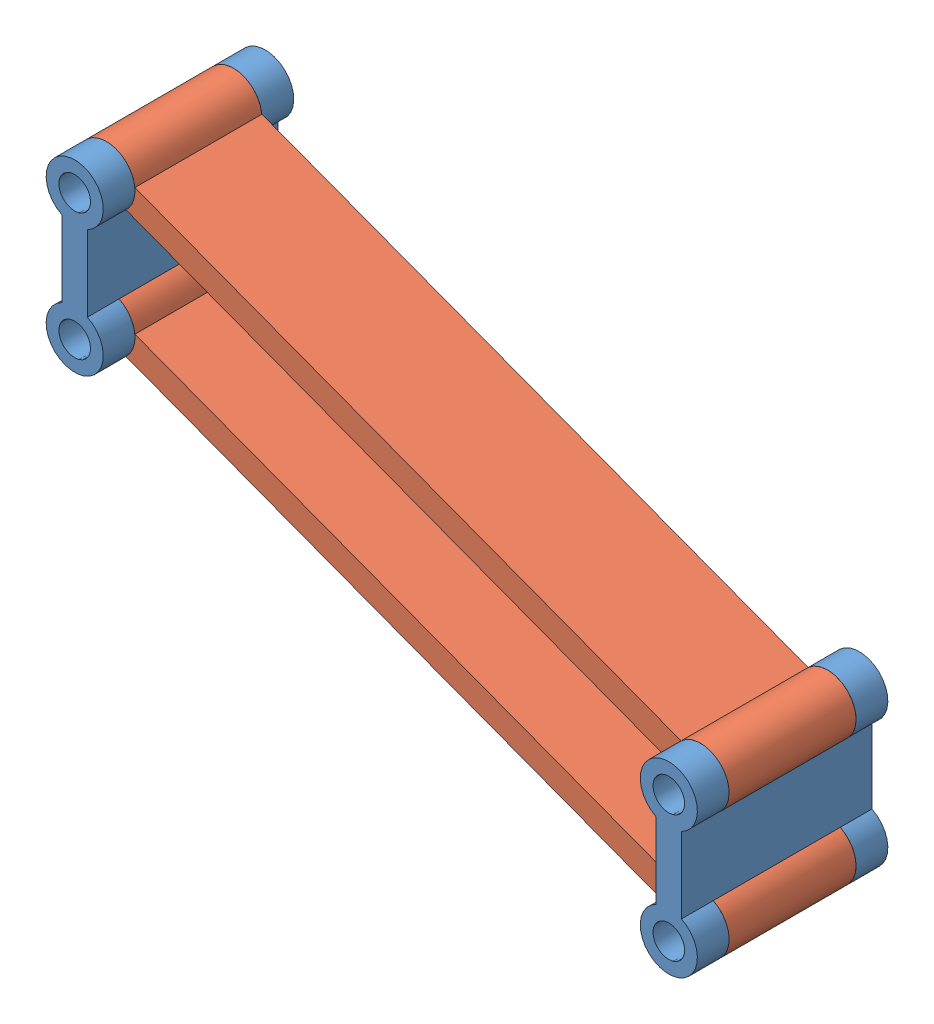
SolidWorks assembly Assem1, configuration Default. Lengths in mm.
Overall size (254 279.4 38.1).
4 component instances, 2 part files, 4 mates.
Components (placement in the parent):
- Chassis_Mount-1: Chassis_Mount [Default] at origin size (11.43 36.83 38.1)
- Lower_A_Arm-1: Lower_A_Arm [Default] at (0 25.4 0) x (0.935639 -0.352959 0) z (0 0 1) size (138.43 11.43 25.4)
- Chassis_Mount-2: Chassis_Mount [Default] at (118.8261 -44.8259 0) size (11.43 36.83 38.1)
- Lower_A_Arm-2: Lower_A_Arm [Default] x (0.935639 -0.352959 0) z (0 0 1) size (138.43 11.43 25.4)
Mates (geometry in assembly coordinates):
- Hinge1: hinge anti-aligned: cylinder of Lower_A_Arm-1 through (0 25.4 12.7) axis (0 0 -1) radius 3.175; cylinder of Chassis_Mount-1 through (0 25.4 19.05) axis (0 0 -1) radius 3.175; plane of Lower_A_Arm-1 through (0 25.4 12.7) normal (0 0 1); plane of Chassis_Mount-1 through (0 0 12.7) normal (0 0 -1)
- Hinge2: hinge anti-aligned: cylinder of Lower_A_Arm-1 through (118.8261 -19.4259 12.7) axis (0 0 -1) radius 3.175; cylinder of Chassis_Mount-2 through (118.8261 -19.4259 19.05) axis (0 0 -1) radius 3.175; plane of Chassis_Mount-2 through (118.8261 -44.8259 12.7) normal (0 0 -1); plane of Lower_A_Arm-1 through (0 25.4 12.7) normal (0 0 1)
- Hinge3: hinge anti-aligned: cylinder of Lower_A_Arm-2 through (0 0 12.7) axis (0 0 -1) radius 3.175; cylinder of Chassis_Mount-1 through (0 0 19.05) axis (0 0 -1) radius 3.175; plane of Chassis_Mount-1 through (0 0 -12.7) normal (0 0 1); plane of Lower_A_Arm-2 through (0 0 -12.7) normal (0 0 -1)
- Hinge4: hinge anti-aligned: cylinder of Lower_A_Arm-2 through (118.8261 -44.8259 12.7) axis (0 0 -1) radius 3.175; cylinder of Chassis_Mount-2 through (118.8261 -44.8259 19.05) axis (0 0 -1) radius 3.175; plane of Lower_A_Arm-2 through (0 0 -12.7) normal (0 0 -1); plane of Chassis_Mount-2 through (118.8261 -44.8259 -12.7) normal (0 0 1)
